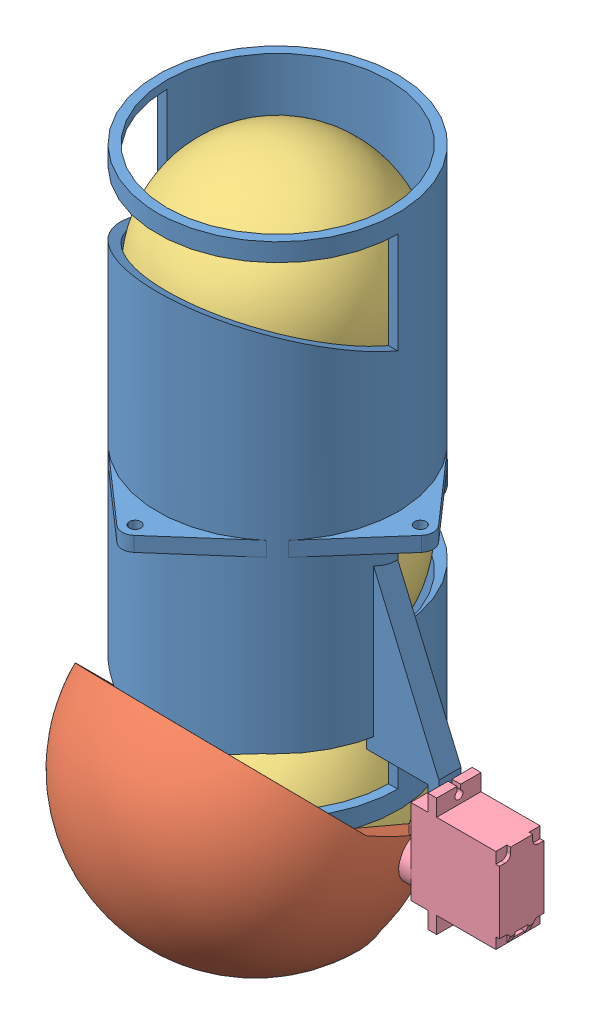
SolidWorks assembly Mekanizma, configuration Default. Lengths in mm.
Overall size (116.83 207.02 102.88).
8 component instances, 5 part files, 8 mates.
Components (placement in the parent):
- Boru-1: Boru [Default] at (55.1923 53.1413 191.9963) size (90.62 140 82)
- kapak-1: kapak [Default] at (57.0571 51.5023 199.9959) x (0.010188 0.999946 -0.002227) z (-0.999933 0.010175 -0.005504) size (68.28 49.38 80)
- TenisTopu-1: TenisTopu [Default] at (55.1923 43.1413 191.9963) x (-0.987016 0.150813 0.055275) z (-0.113186 -0.408868 -0.905547) size (60 60 60)
- TenisTopu-2: TenisTopu [Default] at (55.1923 163.1413 191.9963) x (-0.04337 0.750665 -0.659258) z (0.095194 0.659982 0.745226) size (60 60 60)
- TenisTopu-3: TenisTopu [Default] at (55.1923 103.1413 191.9963) x (-0.665256 0.590154 0.457332) z (0.715669 0.329524 0.615818) size (60 60 60)
- assembly-1: assembly [Varsayılan] at (112.1424 171.5922 194.9963) x (0 1 0) z (0 0 1) size (32 31 12)
  - body-1: body [Varsayılan] at (-117.2872 -12.0692 0) size (32 28 12)
  - gear-1: gear [Varsayılan] at (-122.7872 18.9308 0) x (0.982136 0 -0.188173) z (0 -1 0) size (5 5 3)
Mates (geometry in assembly coordinates):
- Tangent2: tangent anti-aligned: sphere of TenisTopu-2; sphere of TenisTopu-3
- Tangent4: tangent anti-aligned: sphere of TenisTopu-1; sphere of TenisTopu-3
- Tangent5: tangent aligned: cylinder of Boru-1 through (55.1923 193.1413 191.9963) axis (0 -1 0) radius 30; sphere of TenisTopu-2
- Tangent9: tangent aligned: cylinder of Boru-1 through (55.1923 193.1413 191.9963) axis (0 -1 0) radius 30; sphere of TenisTopu-3
- Parallel4: parallel anti-aligned: plane of Boru-1 through (55.1923 53.1413 191.9963) normal (0 -1 0); plane of assembly-1/body-1 through (100.2116 65.805 188.9963) normal (0 1 0)
- Tangent12: tangent aligned: cylinder of Boru-1 through (55.1923 193.1413 191.9963) axis (0 -1 0) radius 30; sphere of TenisTopu-1
- Concentric5: concentric anti-aligned: circle of Boru-1; circle of assembly-1/body-1
- Tangent13: tangent: curve of kapak-1; circle of assembly-1/gear-1
